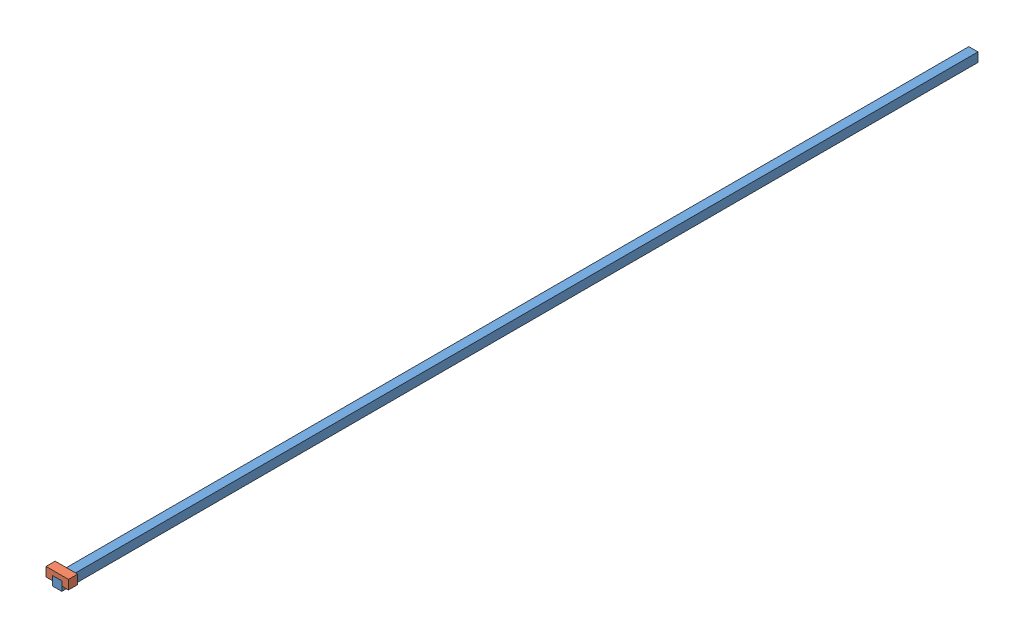
SolidWorks assembly master_assembly_001, configuration Default. Lengths in mm.
Overall size (49.03 30 2000).
2 component instances, 2 part files, 1 mates.
Components (placement in the parent):
- master_body_001-frame_2020_2000mm_4-1: master_body_001-frame_2020_2000mm_4 [Default] at origin size (20 20 2000)
- Copy of Copy of Part3-1: Copy of Copy of Part3 [Default] at (625.9328 58.5348 -7924.4014) x (0 0 -1) z (1 0 0) size (20 20 49.03)
Mates (geometry in assembly coordinates):
- Width2: width: plane of Copy of Copy of Part3-1 through (625.9328 58.5348 2000) normal (0 0 1); plane of master_body_001-frame_2020_2000mm_4-1 through (625.9328 58.5348 1980) normal (0 0 -1); plane of Copy of Copy of Part3-1 through (0 0 2000) normal (0 0 1); plane of master_body_001-frame_2020_2000mm_4-1 through (0 0 0) normal (0 0 -1)
